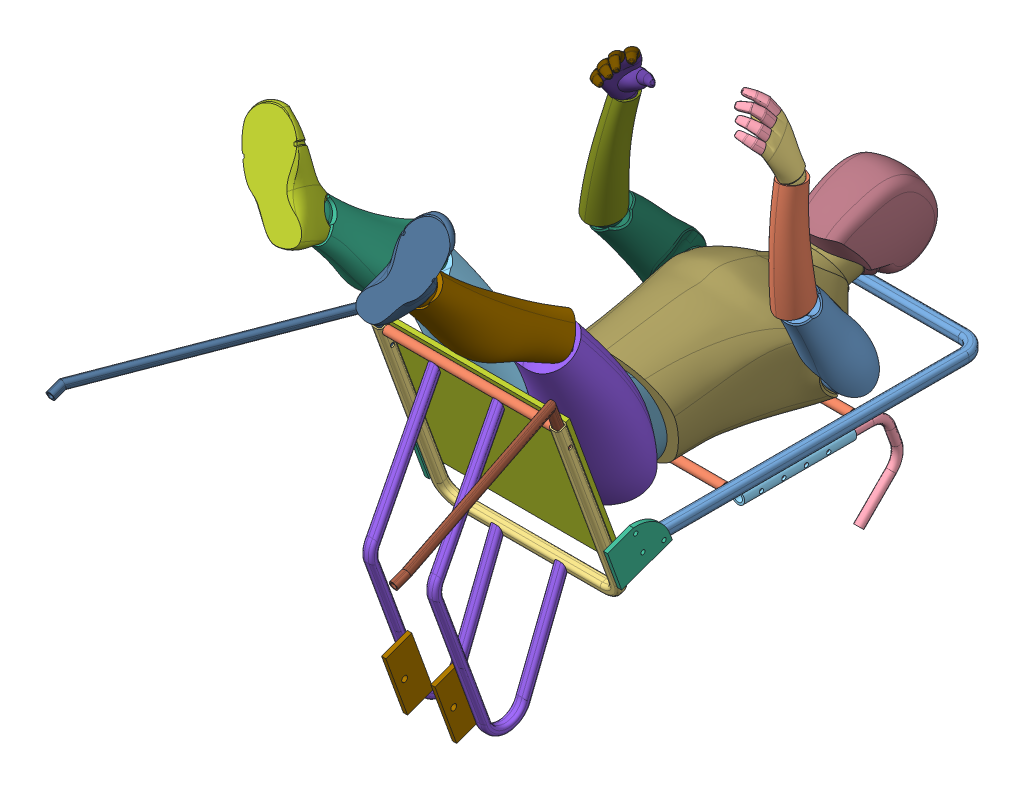
SolidWorks assembly noWheelTrailRider_edited, configuration Default. Lengths in mm.
Overall size (839.89 1499.65 1685.87).
39 component instances, 28 part files, 66 mates.
Components (placement in the parent):
- 02-21Back Seat Platform-U Beam-1: 02-21Back Seat Platform-U Beam [Default] at (-280.186 14.8002 533.2311) size (445 25 862.5)
- 02-21Circular Beam-1: 02-21Circular Beam [Default] at (-267.686 14.8002 -26.7689) size (395 20 20)
- 02-21Circular Beam-2: 02-21Circular Beam [Default] at (-267.686 14.8002 273.2311) size (395 20 20)
- 02-21Circular Beam-3: 02-21Circular Beam [Default] at (-267.686 342.5505 678.3918) x (1 0 0) z (0 -0.233979 0.972242) size (395 20 20)
- 02-21Seat Platform-1: 02-21Seat Platform [Default] at (-280.186 351.954 681.8144) x (0 0.939693 0.34202) z (-1 0 0) size (462.5 25 445)
- 02-21Handle Bar-1: 02-21Handle Bar [Default] at (139.814 -7.6998 159.7311) x (0 0.939693 0.34202) z (0 -0.34202 0.939693) size (273.13 20.68 248.34)
- 02-21Handle Bar Slot-1: 02-21Handle Bar Slot [Default] at (139.814 -187.6998 -58.438) x (0 0 1) z (0 -1 0) size (265 30 30)
- 02-21Handle Bar Slot-2: 02-21Handle Bar Slot [Default] at (-291.0833 172.3002 -58.438) x (0 0 1) z (0 1 0) size (265 30 30)
- 02-21Handle Bar-2: 02-21Handle Bar [Default] at (-291.0833 -7.6998 159.7311) x (0 0.939693 0.34202) z (0 -0.34202 0.939693) size (273.13 20.68 248.34)
- 02-21Hinge-3: 02-21Hinge [Default] at (-292.686 -37.5952 553.3323) x (0 0.939693 0.34202) z (0 -0.34202 0.939693) size (97.1 10 127)
- 02-21Hinge-4: 02-21Hinge [Default] at (162.314 -37.5952 553.3323) x (0 0.939693 0.34202) z (0 -0.34202 0.939693) size (97.1 10 127)
- 02-21Seat-2: 02-21Seat [Default] at (-72.4813 181.1079 595.6875) x (0 0.939693 0.34202) z (1 0 0) size (380 10 439)
- Lower Wheel-1: Lower Wheel [Default] at (724.3679 -14.7342 849.8586) x (0 0.939693 0.34202) z (-1 0 0) size (678.34 305.83 177.58)
  - 02-21Lower Wheel Support-1: 02-21Lower Wheel Support [Default] at (-161.3811 20.8246 719.0539) x (1 0 0) z (0 -1 0) size (678.34 26.58 264.21)
  - 02-21Lower Wheel Support-2: 02-21Lower Wheel Support [Default] at (-161.3811 20.8246 870.0539) x (1 0 0) z (0 -1 0) size (678.34 26.58 264.21)
  - 02-21Wheel Platform-1: 02-21Wheel Platform [Default] at (-243.2393 -2.3689 731.5539) x (1 0 0) z (0 -1 0) size (150 10 65)
  - 02-21Wheel Platform-3: 02-21Wheel Platform [Default] at (-243.2393 -2.3689 847.5539) x (1 0 0) z (0 -1 0) size (150 10 65)
- 02-21(Left)Free Wheel Leg-1: 02-21(Left)Free Wheel Leg [Left] at (-280.186 257.9848 647.6124) x (0 0.939693 0.34202) z (0 -0.34202 0.939693) size (344.97 419.89 539.5)
- 02-21(Right)Free Wheel Leg-1: 02-21(Right)Free Wheel Leg [Left] at (139.814 257.9848 647.6124) x (0 0.939693 0.34202) z (0 -0.34202 0.939693) size (373.05 219.5 539.5)
- Articulated_Dummy-1: Articulated_Dummy [Default] at (-71.3146 59.1763 1362.0661) x (0.002657 -0.994892 -0.100914) z (0.000499 0.100916 -0.994895) size (1052.64 592.75 1430.49)
  - Torso-1: Torso [Default] at origin size (276.17 406.18 676.75)
  - Head-1: Head [Default] at (272.4966 0 13.9002) x (0.984808 0 0.173648) z (-0.173648 0 0.984808) size (223.51 154.11 248.99)
  - Pelvis-1: Pelvis [Default] at (-175.9416 -0.0047 21.1469) x (0.984808 0 -0.173648) z (0.173648 0 0.984808) size (220.9 294.19 237.82)
  - UpperArm_R-1: UpperArm_R [Default] at (-1164.6978 40.5521 782.9918) x (0.480784 0.0664 -0.874321) z (0.876833 -0.032757 0.479678) size (145.29 112.21 352.1)
  - LowerArm_R-1: LowerArm_R [Default] at (-1109.8206 -350.8514 1409.8475) x (-0.021504 -0.067308 -0.9975) z (0.939381 0.340144 -0.043203) size (97.1 110.82 304.02)
  - Hand_R-1: Hand_R [Default] at (-1026.554 -211.1082 756.2464) x (0.450032 0.495206 -0.74313) z (0.803724 0.138099 0.578754) size (143.51 200.25 239.15)
    - Hand_R-1: Hand_R [Default] at origin size (143.51 200.25 232.94)
    - Fingers_R-1: Fingers_R [Default] at origin size (103.08 62.21 73.67)
  - UpperArm_L-1: UpperArm_L [Default] at (-1154.4506 48.1192 789.555) x (0.383712 -0.421381 -0.821707) z (0.901636 -0.021319 0.431969) size (149.95 126.7 354.11)
  - LowerArm_L-1: LowerArm_L [Default] at (-1237.175 109.018 1373.4583) x (0.022959 0.087177 -0.995928) z (0.993849 -0.109941 0.013288) size (97.1 110.82 304.02)
  - Hand_L-1: Hand_L [Default] at (-1158.857 102.2382 896.6784) x (0.400695 -0.340847 -0.850451) z (0.891217 -0.070337 0.448091) size (143.54 200.25 239.15)
    - Hand_L-1: Hand_L [Default] at origin size (143.54 200.25 232.94)
    - Fingers_L-1: Fingers_L [Default] at origin size (103.08 62.28 73.68)
  - UpperLeg_R-1: UpperLeg_R [Default] at (-846.6749 137.4213 675.3146) x (0.202826 -0.686929 -0.697847) z (0.931594 -0.084173 0.35362) size (212.64 165.47 563.01)
  - LowerLeg_R-1: LowerLeg_R [Default] at (-769.3096 25.6211 503.3729) x (0.62768 -0.522628 -0.576956) z (0.723278 0.117422 0.6805) size (159.05 194.06 506.09)
  - Foot_R-1: Foot_R [Default] at (-744.6941 -0.9436 485.0971) x (0.785483 -0.333883 -0.521094) z (0.604301 0.232074 0.762209) size (250.01 160.41 191.51)
  - UpperLeg_L-1: UpperLeg_L [Default] at (-839.4632 -171.6805 657.1156) x (0.179608 0.724804 -0.665132) z (0.920043 0.115573 0.374385) size (212.64 165.47 563.01)
  - LowerLeg_L-1: LowerLeg_L [Default] at (-771.1336 -69.7092 493.1456) x (0.561883 0.655703 -0.504322) z (0.718877 -0.085418 0.689869) size (159.05 194.91 471.32)
  - Foot_L-1: Foot_L [Default] at (-730.9582 -37.7524 417.9636) x (0.868174 0.214838 -0.447345) z (0.453027 0.02488 0.89115) size (250.8 160.43 191.19)
Mates (geometry in assembly coordinates):
- Coincident1: coincident aligned: line of 02-21Back Seat Platform-U Beam-1 through (-280.186 14.8002 -26.7689) axis (1 0 0); line of 02-21Circular Beam-1 through (-267.686 14.8002 -26.7689) axis (1 0 0)
- Coincident2: coincident aligned: line of 02-21Back Seat Platform-U Beam-1 through (-280.186 14.8002 273.2311) axis (1 0 0); line of 02-21Circular Beam-2 through (-267.686 14.8002 273.2311) axis (1 0 0)
- Coincident3: coincident anti-aligned: plane of 02-21Back Seat Platform-U Beam-1 through (-267.686 10.3002 533.2311) normal (1 0 0); plane of 02-21Circular Beam-1 through (-267.686 14.8002 -26.7689) normal (-1 0 0)
- Coincident4: coincident anti-aligned: plane of 02-21Back Seat Platform-U Beam-1 through (-267.686 10.3002 533.2311) normal (1 0 0); plane of 02-21Circular Beam-2 through (-267.686 14.8002 273.2311) normal (-1 0 0)
- Parallel1: parallel aligned: line of 02-21Back Seat Platform-U Beam-1 through (139.814 14.8002 -276.7689) axis (0 0 1); line of 02-21Handle Bar Slot-1 through (139.814 -7.6998 -9.2689) axis (0 0 1)
- Perpendicular1: perpendicular: line of 02-21Back Seat Platform-U Beam-1 through (139.814 14.8002 123.2311) axis (0 -1 0); line of 02-21Handle Bar Slot-1 through (139.814 -7.6998 -9.2689) axis (0 0 1)
- Parallel3: parallel aligned: line of 02-21Handle Bar Slot-1 through (139.814 -7.6998 -9.2689) axis (0 0 1); line of 02-21Handle Bar Slot-2 through (-291.0833 -7.6998 -9.2689) axis (0 0 1)
- Distance2: distance = 25 mm: line of 02-21Back Seat Platform-U Beam-1 through (-280.186 14.8002 533.2311) axis (0 0 -1); line of Handle Bar Slot-2 through (-291.0833 -7.6998 -9.2689) axis (0 0 1)
- Coincident16: coincident anti-aligned: point of Back Seat Platform-U Beam-1; unknown of Handle Bar Slot-1
- Coincident17: coincident anti-aligned: line of 02-21Back Seat Platform-U Beam-1 through (139.814 14.8002 123.2311) axis (0 -1 0); line of 02-21Handle Bar Slot-1 through (139.814 -7.6998 123.2311) axis (0 1 0)
- Concentric1: concentric anti-aligned: cylinder of 02-21Handle Bar-1 through (139.814 -7.6998 159.7311) axis (0 0 -1) radius 10; cylinder of 02-21Handle Bar Slot-1 through (139.814 -7.6998 -9.2689) axis (0 0 1) radius 10
- Concentric2: concentric anti-aligned: cylinder of 02-21Handle Bar Slot-2 through (-291.0833 -7.6998 -9.2689) axis (0 0 1) radius 10; cylinder of 02-21Handle Bar-2 through (-291.0833 -7.6998 159.7311) axis (0 0 -1) radius 10
- Coincident25: coincident anti-aligned: circle of Wheel Platform-1; circle of Wheel-1
- Coincident26: coincident aligned: circle of Wheel-1; circle of Wheel Platform-2
- Parallel9: parallel aligned: line of 02-21Circular Beam-3 through (-267.686 342.5505 678.3918) axis (1 0 0); line of 02-21Seat Platform-1 through (-280.186 304.9694 664.7134) axis (1 0 0)
- Coincident39: coincident: plane of assembly; point of 02-21Circular Beam-3; plane of 02-21Seat Platform-1 through (-267.686 350.4149 686.043) normal (1 0 0)
- Coincident40: coincident: line of assembly; point of 02-21Circular Beam-3; line of 02-21Seat Platform-1 through (-267.686 351.954 681.8144) axis (0 -0.939693 -0.34202)
- Coincident41: coincident: line of 02-21Circular Beam-3 through (-267.686 342.5505 678.3918) axis (1 0 0)
- Coincident42: coincident: line of 02-21Circular Beam-3 through (-267.686 342.5505 678.3918) axis (1 0 0)
- Parallel12: parallel aligned: plane of 02-21Seat Platform-1 through (-284.686 356.2293 670.0683) normal (0 0.34202 -0.939693); plane of 02-21Free Wheel Leg-2 through (141.314 261.234 638.6853) normal (0 0.34202 -0.939693)
- Parallel13: parallel aligned: plane of 02-21Seat Platform-1 through (-284.686 356.2293 670.0683) normal (0 0.34202 -0.939693); plane of 02-21Free Wheel Leg-1 through (-278.686 261.234 638.6853) normal (0 0.34202 -0.939693)
- Coincident53: coincident aligned: line of 02-21Seat Platform-1 through (-292.686 -31.7809 537.3575) axis (0 -0.34202 0.939693); line of Hinge-3 through (-292.686 5.8414 433.9914) axis (0 -0.34202 0.939693)
- Coincident54: coincident aligned: plane of 02-21Seat Platform-1 through (-284.686 347.6788 693.5606) normal (0 -0.34202 0.939693); plane of Hinge-3 through (-302.686 -37.5952 553.3323) normal (0 -0.34202 0.939693)
- Coincident55: coincident aligned: line of 02-21Seat Platform-1 through (152.314 -31.7809 537.3575) axis (0 -0.34202 0.939693); line of Hinge-4 through (152.314 5.8414 433.9914) axis (0 -0.34202 0.939693)
- Coincident56: coincident aligned: plane of 02-21Seat Platform-1 through (-284.686 347.6788 693.5606) normal (0 -0.34202 0.939693); plane of Hinge-4 through (152.314 -37.5952 553.3323) normal (0 -0.34202 0.939693)
- Coincident57: coincident anti-aligned: circle of Back Seat Platform-U Beam-1; circle of Hinge-4
- Coincident58: coincident anti-aligned: circle of Back Seat Platform-U Beam-1; circle of Hinge-4
- Coincident66: coincident anti-aligned: plane of 02-21Seat Platform-1 through (-284.686 356.2293 670.0683) normal (0 0.34202 -0.939693); plane of Seat-2 through (-72.4813 177.6877 605.0844) normal (0 -0.34202 0.939693)
- Parallel14: parallel aligned: plane of 02-21Seat Platform-1 through (152.314 -34.859 545.8148) normal (1 0 0); plane of Seat-2 through (147.0187 -0.8539 540.1006) normal (1 0 0)
- Coincident68: coincident aligned: plane of 02-21Seat Platform-1 through (144.314 353.4931 677.5858) normal (0 0.939693 0.34202); plane of Seat-2 through (147.0187 356.2293 670.0683) normal (0 0.939693 0.34202)
- Concentric3: concentric aligned: cylinder of 02-21Handle Bar-1 through (149.814 -7.6998 109.7311) axis (-1 0 0) radius 5; cylinder of 02-21Handle Bar Slot-1 through (154.814 -7.6998 109.7311) axis (-1 0 0) radius 5
- Concentric4: concentric anti-aligned: cylinder of 02-21Handle Bar Slot-1 through (154.814 -7.6998 109.7311) axis (-1 0 0) radius 5; cylinder of 02-21Handle Bar Slot-2 through (-306.0833 -7.6998 109.7311) axis (1 0 0) radius 5
- Concentric5: concentric anti-aligned: cylinder of 02-21Handle Bar Slot-2 through (-306.0833 -7.6998 109.7311) axis (1 0 0) radius 5; cylinder of 02-21Handle Bar-2 through (-281.0833 -7.6998 109.7311) axis (-1 0 0) radius 5
- Concentric6: concentric anti-aligned: cylinder of 02-21Back Seat Platform-U Beam-1 through (-292.686 14.8002 503.2311) axis (1 0 0) radius 5; cylinder of Hinge-3 through (-292.686 14.8002 503.2311) axis (-1 0 0) radius 5
- Parallel20: parallel aligned: line of Lower Wheel Support-1 through (-143.3064 342.5505 678.3918) axis (0 0.422618 0.906308); line of Lower Wheel Support-2 through (1.6936 342.5505 678.3918) axis (0 0.422618 0.906308)
- Coincident78: coincident aligned: line of Lower Wheel Support-1 through (-130.8064 -388.705 683.2525) axis (0 0.939693 0.34202); line of Wheel Platform-1 through (-130.8064 -378.8383 686.8437) axis (0 0.939693 0.34202)
- Coincident79: coincident aligned: line of Wheel Platform-2 through (-10.8064 -378.8383 686.8437) axis (0 0.939693 0.34202); line of Lower Wheel Support-2 through (-10.8064 -388.705 683.2525) axis (0 0.939693 0.34202)
- Coincident83: coincident anti-aligned: plane of 02-21Seat Platform-1 through (-284.686 355.2032 672.8873) normal (0 -0.34202 0.939693); plane of 02-21Free Wheel Leg-1 through (-278.686 261.234 638.6853) normal (0 0.34202 -0.939693)
- Coincident84: coincident anti-aligned: plane of 02-21Seat Platform-1 through (-289.686 350.4149 686.043) normal (1 0 0); plane of 02-21Free Wheel Leg-1 through (-289.686 257.4717 649.0219) normal (-1 0 0)
- Coincident85: coincident anti-aligned: plane of 02-21Seat Platform-1 through (-284.686 355.2032 672.8873) normal (0 -0.34202 0.939693); plane of 02-21Free Wheel Leg-2 through (141.314 261.234 638.6853) normal (0 0.34202 -0.939693)
- Coincident86: coincident anti-aligned: plane of 02-21Seat Platform-1 through (149.314 -34.859 545.8148) normal (-1 0 0); plane of 02-21Free Wheel Leg-2 through (149.314 257.4717 649.0219) normal (1 0 0)
- Coincident89: coincident aligned: plane of 02-21Free Wheel Leg-1 through (-278.686 407.5601 693.1019) normal (0 0.984808 -0.173648); plane of 02-21Free Wheel Leg-2 through (141.314 407.5601 693.1019) normal (0 0.984808 -0.173648)
- Coincident94: coincident: line of Lower Wheel Support-1 through (-120.8064 -309.9004 716.7238) axis (0 -0.34202 0.939693)
- Coincident95: coincident aligned: line of 02-21Seat Platform-1 through (-143.3064 -70.9077 527.9054) axis (0 -0.34202 0.939693); line of Lower Wheel Support-1 through (-143.3064 -74.0445 536.5239) axis (0 -0.34202 0.939693)
- Parallel21: parallel aligned: line of 02-21Seat Platform-1 through (1.6936 -70.9077 527.9054) axis (0 -0.34202 0.939693); line of Lower Wheel Support-2 through (1.6936 -74.0445 536.5239) axis (0 -0.34202 0.939693)
- Coincident98: coincident aligned: line of Lower Wheel Support-1 through (-138.8064 -359.1911 552.459) axis (-1 0 0); line of Lower Wheel Support-2 through (6.1936 -359.1911 552.459) axis (-1 0 0)
- Parallel26: parallel anti-aligned: line of Lower Wheel Support-1 through (-120.8064 -309.9004 716.7238) axis (0 -0.34202 0.939693); line of 02-21Free Wheel Leg-1 through (-280.186 -329.3807 853.1591) axis (0 0.34202 -0.939693)
- Distance3: distance = 734.3042 mm: point of ?; point of ?
- Concentric9: concentric aligned: cylinder of 02-21Seat Platform-1 through (152.314 304.9694 664.7134) axis (-1 0 0) radius 5; cylinder of 02-21Free Wheel Leg-1 through (-270.686 304.9694 664.7134) axis (-1 0 0) radius 5
- Coincident103: coincident anti-aligned: plane of 02-21Seat Platform-1 through (-284.686 347.6788 693.5606) normal (0 -0.34202 0.939693); plane of Lower Wheel-1/02-21Lower Wheel Support-1 through (9.814 -69.5267 541.7102) normal (0 0.34202 -0.939693)
- Coincident104: coincident anti-aligned: plane of 02-21Seat Platform-1 through (-284.686 347.6788 693.5606) normal (0 -0.34202 0.939693); plane of Lower Wheel-1/02-21Lower Wheel Support-2 through (-141.186 -69.5267 541.7102) normal (0 0.34202 -0.939693)
- Coincident105: coincident: plane of 02-21Seat Platform-1 through (-240.186 -84.1929 527.8587) normal (0 -0.939693 -0.34202); line of Lower Wheel-1/02-21Lower Wheel Support-1 through (0.814 -86.9291 535.3763) axis (1 0 0)
- Coincident106: coincident: plane of 02-21Seat Platform-1 through (-240.186 -84.1929 527.8587) normal (0 -0.939693 -0.34202); line of Lower Wheel-1/02-21Lower Wheel Support-2 through (-150.186 -86.9291 535.3763) axis (1 0 0)
- Symmetric2: symmetric aligned: plane of 02-21Seat Platform-1 through (-70.186 351.954 681.8144) normal (1 0 0); plane of Lower Wheel-1/02-21Lower Wheel Support-2 through (-7.186 -77.984 538.632) normal (-1 0 0); plane of Lower Wheel-1/02-21Lower Wheel Support-1 through (-133.186 -77.984 538.632) normal (1 0 0)
- Coincident110: coincident anti-aligned: circle of 02-21Seat Platform-1; circle of 02-21Free Wheel Leg-1
- Coincident111: coincident anti-aligned: plane of 02-21Seat Platform-1 through (-284.686 355.2032 672.8873) normal (0 -0.34202 0.939693); plane of 02-21Free Wheel Leg-1 through (-278.686 261.234 638.6853) normal (0 0.34202 -0.939693)
- Concentric11: concentric aligned: cylinder of 02-21Seat Platform-1 through (152.314 304.9694 664.7134) axis (-1 0 0) radius 5; cylinder of 02-21Free Wheel Leg-3 through (-270.686 304.9694 664.7134) axis (-1 0 0) radius 5
- Coincident112: coincident anti-aligned: plane of 02-21Seat Platform-1 through (-284.686 355.2032 672.8873) normal (0 -0.34202 0.939693); plane of 02-21Free Wheel Leg-3 through (-278.686 261.234 638.6853) normal (0 0.34202 -0.939693)
- Coincident113: coincident anti-aligned: plane of 02-21Seat Platform-1 through (-289.686 350.4149 686.043) normal (1 0 0); plane of 02-21Free Wheel Leg-3 through (-289.686 257.4717 649.0219) normal (-1 0 0)
- Coincident122: coincident anti-aligned: circle of 02-21Seat Platform-1; circle of 02-21(Left)Free Wheel Leg-1
- Coincident123: coincident anti-aligned: plane of 02-21Seat Platform-1 through (-284.686 355.2032 672.8873) normal (0 -0.34202 0.939693); plane of 02-21(Left)Free Wheel Leg-1 through (-278.686 261.234 638.6853) normal (0 0.34202 -0.939693)
- Coincident128: coincident anti-aligned: circle of 02-21Seat Platform-1; circle of 02-21(Right)Free Wheel Leg-1
- Coincident129: coincident anti-aligned: plane of 02-21Seat Platform-1 through (-284.686 355.2032 672.8873) normal (0 -0.34202 0.939693); plane of 02-21(Right)Free Wheel Leg-1 through (141.314 261.234 638.6853) normal (0 0.34202 -0.939693)
- Coincident130: coincident anti-aligned: plane of 02-21Back Seat Platform-U Beam-1 through (-280.186 14.8002 533.2311) normal (0 1 0); plane of Articulated_Dummy-1 through (-70.186 14.8002 33.6283) normal (0 -1 0)
- Coincident131: coincident aligned: plane of 02-21Seat Platform-1 through (-70.186 351.954 681.8144) normal (1 0 0); plane of Articulated_Dummy-1 through (-70.186 59.1763 1362.0661) normal (1 0 0)
- Tangent1: tangent anti-aligned: plane of 02-21Seat-2 through (-72.4813 181.1079 595.6875) normal (0 0.34202 -0.939693); face of Articulated_Dummy-1/Pelvis-1
